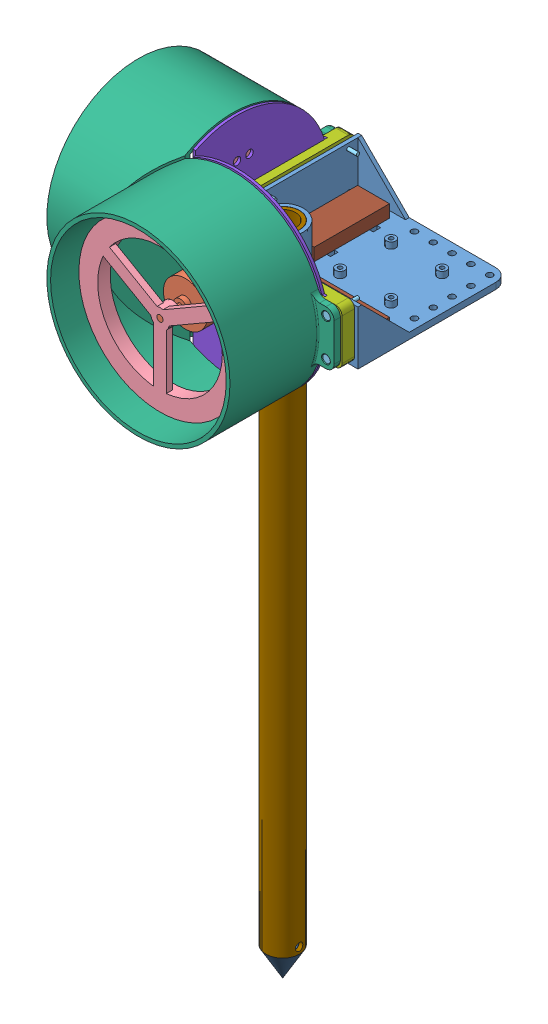
SolidWorks assembly Inverted Pendulum, configuration Default. Lengths in mm.
Overall size (205 592.54 205).
41 component instances, 11 part files, 44 mates.
Components (placement in the parent):
- Base-1: Base [Default] at (0 -16.42 0) size (120 42.84 120)
- Axis-1: Axis [Default] at (-71.05 2.5 0) x (0 0 1) z (-1 0 0) size (176.68 176.68 95.5)
  - Motor-1: Motor [Default] x (0.707107 0.707107 0) z (0.707107 -0.707107 0) size (35 53.5 35)
  - Motor Plate-1: Motor Plate [Default] at (0 0 -26.65) x (0.707107 0.707107 0) z (-0.707107 0.707107 0) size (50 2.8 50)
  - Reaction Wheel-1: Reaction Wheel [Default] at (0 0 26.75) x (0.5 -0.866025 0) z (-0.866025 -0.5 0) size (129.34 10 129.34)
  - Screw-1: Screw [M3x5.5 Flat] at (8.4853 8.4853 -23.3783) x (0.707107 0.707107 0) z (-0.707107 0.707107 0) size (5 7.2 5)
  - Screw-2: Screw [M3x5.5 Flat] at (6.5407 -6.5407 -23.3783) x (0.707107 0.707107 0) z (-0.707107 0.707107 0) size (5 7.2 5)
  - Screw-3: Screw [M3x5.5 Flat] at (-6.5407 6.5407 -23.3783) x (0.707107 0.707107 0) z (-0.707107 0.707107 0) size (5 7.2 5)
  - Screw-4: Screw [M3x5.5 Flat] at (-8.4853 -8.4853 -23.3783) x (0.707107 0.707107 0) z (-0.707107 0.707107 0) size (5 7.2 5)
  - Screw-5: Screw [M3x25 Flat] at (-14.92 14.92 -38.525) x (0.999986 0.005309 0) z (0.005309 -0.999986 0) size (6 25 6)
  - Screw-6: Screw [M3x25 Flat] at (-14.92 -14.92 -38.525) x (0.707107 0.707107 0) z (0.707107 -0.707107 0) size (6 25 6)
  - Screw-7: Screw [M3x25 Flat] at (14.92 -14.92 -38.525) x (0.707107 0.707107 0) z (0.707107 -0.707107 0) size (6 25 6)
  - Screw-8: Screw [M3x25 Flat] at (14.92 14.92 -38.525) x (0.707107 0.707107 0) z (0.707107 -0.707107 0) size (6 25 6)
  - Shield-1: Shield [Default] at (0 0 6.45) size (159 146 75)
  - Screw-9: Screw [M3x25 Flat] at (-79.5 14.92 -39.875) x (0.707107 0.707107 0) z (0.707107 -0.707107 0) size (6 25 6)
  - Screw-10: Screw [M3x25 Flat] at (-79.5 -14.92 -39.875) x (0.707107 0.707107 0) z (0.707107 -0.707107 0) size (6 25 6)
  - Shock Plate-1: Shock Plate [Default] at (-32.29 0 -36.05) x (-1 0 0) z (0 1 0) size (110 10 42.84)
  - Rear Shield-1: Rear Shield [Wire Holes] at (0.0004 0 -33.5) x (1 0 0) z (0 -1 0) size (105.21 2.2 71.58)
  - Rear Shield-2: Rear Shield [Default] at (0.0004 0 -33.5) x (1 0 0) z (0 1 0) size (105.21 2.2 71.58)
- Axis-2: Axis [Reverse] at (0 2.5 71.05) x (-1 0 0) z (0 0 1) size (176.68 176.68 95.5)
  - Motor-1: Motor [Default] x (0.707107 0.707107 0) z (0.707107 -0.707107 0) size (35 53.5 35)
  - Motor Plate-1: Motor Plate [Default] at (0 0 -26.65) x (0.707107 0.707107 0) z (-0.707107 0.707107 0) size (50 2.8 50)
  - Reaction Wheel-1: Reaction Wheel [Default] at (0 0 26.75) x (0.5 -0.866025 0) z (-0.866025 -0.5 0) size (129.34 10 129.34)
  - Screw-1: Screw [M3x5.5 Flat] at (8.4853 8.4853 -23.3783) x (0.707107 0.707107 0) z (-0.707107 0.707107 0) size (5 7.2 5)
  - Screw-2: Screw [M3x5.5 Flat] at (6.5407 -6.5407 -23.3783) x (0.707107 0.707107 0) z (-0.707107 0.707107 0) size (5 7.2 5)
  - Screw-3: Screw [M3x5.5 Flat] at (-6.5407 6.5407 -23.3783) x (0.707107 0.707107 0) z (-0.707107 0.707107 0) size (5 7.2 5)
  - Screw-4: Screw [M3x5.5 Flat] at (-8.4853 -8.4853 -23.3783) x (0.707107 0.707107 0) z (-0.707107 0.707107 0) size (5 7.2 5)
  - Screw-5: Screw [M3x25 Flat] at (-14.92 14.92 -38.525) x (0.999986 0.005309 0) z (0.005309 -0.999986 0) size (6 25 6)
  - Screw-6: Screw [M3x25 Flat] at (-14.92 -14.92 -38.525) x (0.707107 0.707107 0) z (0.707107 -0.707107 0) size (6 25 6)
  - Screw-7: Screw [M3x25 Flat] at (14.92 -14.92 -38.525) x (0.707107 0.707107 0) z (0.707107 -0.707107 0) size (6 25 6)
  - Screw-8: Screw [M3x25 Flat] at (14.92 14.92 -38.525) x (0.707107 0.707107 0) z (0.707107 -0.707107 0) size (6 25 6)
  - Shield-1: Shield [Default] at (0 0 6.45) size (159 146 75)
  - Screw-9: Screw [M3x25 Flat] at (-79.5 14.92 -39.875) x (0.707107 0.707107 0) z (0.707107 -0.707107 0) size (6 25 6)
  - Screw-10: Screw [M3x25 Flat] at (-79.5 -14.92 -39.875) x (0.707107 0.707107 0) z (0.707107 -0.707107 0) size (6 25 6)
  - Shock Plate-1: Shock Plate [Default] at (-32.29 0 -36.05) x (-1 0 0) z (0 1 0) size (110 10 42.84)
  - Rear Shield-1: Rear Shield [Default] at (0.0004 0 -33.5) x (1 0 0) z (0 -1 0) size (105.21 2.2 71.58)
  - Rear Shield-2: Rear Shield [Wire Holes] at (0.0004 0 -33.5) x (1 0 0) z (0 1 0) size (105.21 2.2 71.58)
- Pipe-1: Pipe [Default] at (0 -228.58 0) x (0 0 -1) z (1 0 0) size (26.7 500 26.7)
- Tip-1: Tip [Default] at (0 -485.1414 0) size (26.7 33.12 26.7)
- ESC-1: ESC [Default] at (51.75 -11.42 9.3) size (60 10 25.4)
- ESC-2: ESC [Default] at (-9.3 -11.42 -51.75) x (0 0 -1) z (1 0 0) size (60 10 25.4)
Mates (geometry in assembly coordinates):
- Coincident1: coincident aligned: plane of Base-1 through (0 -16.42 0) normal (0 0 1)
- Coincident2: coincident aligned: plane of Base-1 through (0 -16.42 0) normal (1 0 0)
- Symmetric1: symmetric aligned: plane of Base-1 through (0 21.42 0) normal (0 1 0); plane of Base-1 through (0 -21.42 0) normal (0 -1 0)
- Coincident3: coincident aligned: cone of Screw-8 through (-44.1395 -76.0199 94.0199) axis (0 0 1); cone of Motor Plate-1 through (-44.1395 -76.0199 93.7981) axis (0 0 1)
- Concentric1: concentric anti-aligned: cylinder of Motor-1 through (-50.6802 -69.4792 74.359) axis (0 0 -1) radius 2.5; cylinder of Reaction Wheel-1 through (-50.6802 -69.4792 131.8981) axis (0 0 1) radius 2.5
- Coincident4: coincident aligned: cone of Screw-7 through (-59.1655 -77.9645 94.0199) axis (0 0 1); cone of Motor Plate-1 through (-59.1655 -77.9645 93.7981) axis (0 0 1)
- Coincident5: coincident aligned: plane of Motor-1 through (-50.6802 -69.4792 146.8981) normal (0 0 1); plane of Reaction Wheel-1 through (-50.6802 -69.4792 146.8981) normal (0 0 1)
- Concentric2: concentric aligned: cylinder of Screw-8 through (-44.1395 -76.0199 102.4765) axis (0 0 1) radius 1.35; cylinder of Motor Plate-1 through (-44.1395 -76.0199 92.0981) axis (0 0 1) radius 1.5
- Concentric3: concentric aligned: cylinder of Screw-6 through (-42.195 -60.9939 102.4765) axis (0 0 1) radius 1.35; cylinder of Motor Plate-1 through (-42.195 -60.9939 92.0981) axis (0 0 1) radius 1.5
- Concentric4: concentric anti-aligned: cylinder of Motor-1 through (-50.6802 -69.4792 74.359) axis (0 0 -1) radius 2.5; cylinder of Motor Plate-1 through (-50.6802 -69.4792 92.0981) axis (0 0 1) radius 5.75
- Coincident6: coincident aligned: cone of Motor Plate-1 through (-57.221 -62.9384 93.7981) axis (0 0 1); cone of Screw-9 through (-57.221 -62.9384 94.0199) axis (0 0 1)
- Coincident7: coincident aligned: cone of Screw-6 through (-42.195 -60.9939 94.0199) axis (0 0 1); cone of Motor Plate-1 through (-42.195 -60.9939 93.7981) axis (0 0 1)
- Coincident8: coincident aligned: cone of Screw-4 through (-35.7603 -84.3991 93.2981) axis (0 0 -1); cone of Motor Plate-1 through (-35.7603 -84.3991 94.8981) axis (0 0 -1)
- Concentric5: concentric aligned: cylinder of Motor Plate-1 through (-57.221 -62.9384 92.0981) axis (0 0 1) radius 1.5; cylinder of Screw-9 through (-57.221 -62.9384 102.4765) axis (0 0 1) radius 1.35
- Concentric6: concentric aligned: cylinder of Screw-7 through (-59.1655 -77.9645 102.4765) axis (0 0 1) radius 1.35; cylinder of Motor Plate-1 through (-59.1655 -77.9645 92.0981) axis (0 0 1) radius 1.5
- Coincident9: coincident anti-aligned: plane of Motor-1 through (-48.9125 -67.7114 94.8981) normal (0 0 -1); plane of Motor Plate-1 through (-35.7603 -84.3991 94.8981) normal (0 0 1)
- Concentric7: concentric anti-aligned: cylinder of Motor-1 through (-42.195 -60.9939 99.8981) axis (0 0 -1) radius 1.5; cylinder of Motor Plate-1 through (-42.195 -60.9939 92.0981) axis (0 0 1) radius 1.5
- Concentric8: concentric anti-aligned: cylinder of Motor-1 through (-44.1395 -76.0199 99.8981) axis (0 0 -1) radius 1.5; cylinder of Motor Plate-1 through (-44.1395 -76.0199 92.0981) axis (0 0 1) radius 1.5
- Concentric9: concentric anti-aligned: cylinder of Screw-2 through (-65.6002 -84.3991 81.0915) axis (0 0 -1) radius 1.35; cylinder of Motor Plate-1 through (-65.6002 -84.3991 92.0981) axis (0 0 1) radius 1.5
- Concentric10: concentric anti-aligned: cylinder of Screw-4 through (-35.7603 -84.3991 81.0915) axis (0 0 -1) radius 1.35; cylinder of Motor Plate-1 through (-35.7603 -84.3991 92.0981) axis (0 0 1) radius 1.5
- Coincident10: coincident aligned: cone of Screw-3 through (-35.7603 -54.5592 93.2981) axis (0 0 -1); cone of Motor Plate-1 through (-35.7603 -54.5592 94.8981) axis (0 0 -1)
- Concentric11: concentric anti-aligned: cylinder of Screw-3 through (-35.7603 -54.5592 81.0915) axis (0 0 -1) radius 1.35; cylinder of Motor Plate-1 through (-35.7603 -54.5592 92.0981) axis (0 0 1) radius 1.5
- Concentric12: concentric anti-aligned: cylinder of Screw-5 through (-65.6002 -54.5592 81.0915) axis (0 0 -1) radius 1.35; cylinder of Motor Plate-1 through (-65.6002 -54.5592 92.0981) axis (0 0 1) radius 1.5
- Coincident11: coincident aligned: cone of Screw-5 through (-65.6002 -54.5592 93.2981) axis (0 0 -1); cone of Motor Plate-1 through (-65.6002 -54.5592 94.8981) axis (0 0 -1)
- Coincident12: coincident aligned: cone of Screw-2 through (-65.6002 -84.3991 93.2981) axis (0 0 -1); cone of Motor Plate-1 through (-65.6002 -84.3991 94.8981) axis (0 0 -1)
- Concentric16: concentric anti-aligned: cylinder of Base-1 through (90 17.42 -14.92) axis (-1 0 0) radius 1.5; cylinder of Axis-1/Screw-5 through (-26.8184 17.42 -14.92) axis (1 0 0) radius 1.35
- Concentric17: concentric anti-aligned: cylinder of Base-1 through (90 17.42 -79.5) axis (-1 0 0) radius 1.5; cylinder of Axis-1/Screw-9 through (-25.4684 17.42 -79.5) axis (1 0 0) radius 1.35
- Concentric21: concentric anti-aligned: cylinder of Base-1 through (79.5 17.42 -90) axis (0 0 1) radius 1.5; cylinder of Axis-2/Screw-10 through (79.5 17.42 25.4684) axis (0 0 -1) radius 1.35
- Concentric23: concentric: cylinder of Base-1 through (-15.1321 15.1321 -90) axis (0 0 1) radius 1.5; cylinder of Axis-2/Screw-7 through (-14.7055 14.4759 21.9934) axis (0 0 -1) radius 1.35
- Concentric24: concentric anti-aligned: cylinder of Base-1 through (-14.92 17.42 -90) axis (0 0 1) radius 1.5; cylinder of Axis-2/Screw-7 through (-14.92 17.42 26.8184) axis (0 0 -1) radius 1.35
- Concentric25: concentric anti-aligned: cylinder of Base-1 through (0 -21.42 0) axis (0 1 0) radius 13.5; cylinder of Pipe-1 through (0 21.42 0) axis (0 -1 0) radius 13.35
- Coincident17: coincident aligned: plane of Base-1 through (0 21.42 0) normal (0 1 0); plane of Pipe-1 through (0 21.42 0) normal (0 1 0)
- Concentric26: concentric aligned: cylinder of Pipe-1 through (0 21.42 0) axis (0 -1 0) radius 13.35; cylinder of Tip-1 through (0 -509.7153 0) axis (0 -1 0) radius 10.25
- Coincident18: coincident anti-aligned: plane of Pipe-1 through (0 -478.58 0) normal (0 -1 0); plane of Tip-1 through (10.25 -478.58 0) normal (0 1 0)
- Concentric27: concentric aligned: cylinder of Base-1 through (90 0 0) axis (-1 0 0) radius 3; cylinder of Pipe-1 through (13.35 0 0) axis (-1 0 0) radius 3
- Concentric28: concentric aligned: cylinder of Pipe-1 through (13.35 -473.58 0) axis (-1 0 0) radius 3; cylinder of Tip-1 through (13.35 -473.58 0) axis (-1 0 0) radius 3
- Coincident19: coincident anti-aligned: plane of Base-1 through (0 -16.42 0) normal (0 1 0); plane of ESC-1 through (51.75 -16.42 9.3) normal (0 -1 0)
- Coincident20: coincident aligned: plane of Base-1 through (71.75 -21.42 -3.4) normal (0 0 -1); plane of ESC-1 through (21.75 -6.42 -3.4) normal (0 0 -1)
- Coincident21: coincident anti-aligned: plane of Base-1 through (0 -16.42 0) normal (0 1 0); plane of ESC-2 through (-9.3 -16.42 -51.75) normal (0 -1 0)
- Coincident22: coincident aligned: plane of Base-1 through (-22 -21.42 -71.75) normal (-1 0 0); plane of ESC-2 through (-22 -6.42 -21.75) normal (-1 0 0)
- Width1: width anti-aligned: plane of ESC-1 through (81.75 -6.42 22) normal (1 0 0); plane of ESC-1 through (21.75 -6.42 22) normal (-1 0 0); plane of Base-1 through (71.75 -21.42 -3.4) normal (-1 0 0); plane of Base-1 through (31.75 -21.42 -3.4) normal (1 0 0)
- Width2: width anti-aligned: plane of ESC-2 through (3.4 -6.42 -81.75) normal (0 0 -1); plane of ESC-2 through (3.4 -6.42 -21.75) normal (0 0 1); plane of Base-1 through (3.4 -21.42 -71.75) normal (0 0 1); plane of Base-1 through (3.4 -21.42 -31.75) normal (0 0 -1)
- Coincident25: coincident anti-aligned: plane of Base-1 through (-30 -21.42 30) normal (-1 0 0); plane of Axis-1/Shock Plate-1 through (-30 18.92 17.71) normal (1 0 0)
- Coincident26: coincident anti-aligned: plane of Base-1 through (-30 -21.42 30) normal (0 0 1); plane of Axis-2/Shock Plate-1 through (-17.71 -13.92 30) normal (0 0 -1)
